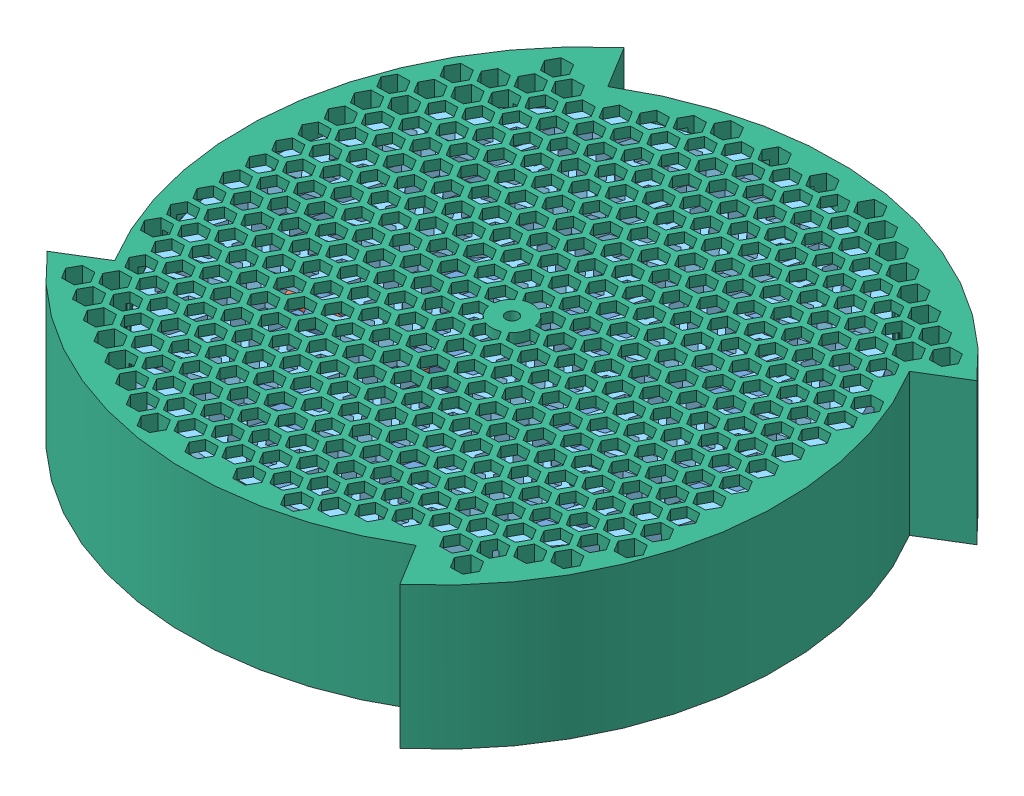
SolidWorks assembly Prototype without internals, configuration Default. Lengths in mm.
Overall size (240.94 41.91 240.94).
9 component instances, 6 part files, 17 mates.
Components (placement in the parent):
- Base-1: Base [Default] at (33.3253 63.9138 106.5179) size (139.7 21.82 139.7)
- Axle-1: Axle [Default] at (56.1853 76.6138 106.5179) x (0 -0.817465 -0.575978) z (1 0 0) size (2.91 3 34.74)
- Axle-2: Axle [Default] at (10.4653 76.6138 106.5179) x (0 -0.966612 0.256244) z (-1 0 0) size (2.91 3 34.74)
- Motor-End Belt-1: Motor-End Belt [Default] at (73.8289 70.2515 121.1027) x (0 -0.000061 1) z (-1 0 0) size (4.5 4.5 3.05)
- Wheel-End Belt-1: Wheel-End Belt [Default] at (73.5749 67.8424 145.4831) x (0 0 1) z (-1 0 0) size (13.65 13.65 3.05)
- Wheel-End Belt-2: Wheel-End Belt [Default] at (-4.5674 67.8424 131.0528) x (0 0 -1) z (1 0 0) size (13.65 13.65 3.05)
- Motor-End Belt-2: Motor-End Belt [Default] at (-4.8214 75.7125 90.6314) x (0 0.347219 -0.937784) z (1 0 0) size (4.5 4.5 3.05)
- Case-1: Case [Default] at (33.3253 66.4538 106.5179) x (0.716089 0 -0.698009) z (0.698009 0 0.716089) size (139.7 31.75 150.25)
- Spinny Boi-1: Spinny Boi [Default] at (33.3253 100.7438 106.5179) x (0.521586 0 0.853199) z (-0.853199 0 0.521586) size (175.26 36.83 175.26)
Mates (geometry in assembly coordinates):
- Coincident12: coincident anti-aligned: plane of Base-1 through (56.1853 76.6138 106.5179) normal (-1 0 0); plane of Axle-1 through (56.1853 76.6138 106.5179) normal (1 0 0)
- Coincident14: coincident: line of Base-1 through (-36.5247 76.6138 106.5179) axis (1 0 0); point of Axle-1
- Coincident17: coincident aligned: plane of Base-1 through (10.4653 76.6138 106.5179) normal (1 0 0); plane of Axle-2 through (10.4653 76.6138 106.5179) normal (1 0 0)
- Coincident18: coincident aligned: line of Base-1 through (-36.5247 76.6138 106.5179) axis (1 0 0); line of Axle-2 through (-24.2747 76.6138 106.5179) axis (1 0 0)
- Coincident24: coincident aligned: plane of Motor-End Belt-1 through (72.3049 76.6138 106.5179) normal (-1 0 0); plane of Wheel-End Belt-1 through (72.3049 67.8424 145.4831) normal (-1 0 0)
- Parallel4: parallel anti-aligned: plane of Base-1 through (33.3253 63.9138 106.5179) normal (1 0 0); plane of Wheel-End Belt-1 through (72.3049 67.8424 145.4831) normal (-1 0 0)
- Coincident27: coincident anti-aligned: line of Axle-1 through (90.9253 76.6138 106.5179) axis (-1 0 0); line of Motor-End Belt-1 through (72.5589 76.6138 106.5179) axis (1 0 0)
- Parallel5: parallel anti-aligned: plane of Axle-1 through (95.1061 75.7512 107.7451) normal (0 -1 -0.000061); plane of Motor-End Belt-1 through (72.5589 75.6129 121.103) normal (0 1 0.000061)
- Distance7: distance = 36.6227 mm aligned: plane of Wheel-End Belt-2 through (-3.2974 67.8424 131.0528) normal (1 0 0); plane of Base-1 through (33.3253 63.9138 106.5179) normal (1 0 0)
- Coincident32: coincident aligned: plane of Wheel-End Belt-2 through (-3.2974 67.8424 131.0528) normal (1 0 0); plane of Motor-End Belt-2 through (-3.2974 76.6138 106.5179) normal (1 0 0)
- Parallel11: parallel anti-aligned: plane of Axle-2 through (-28.4555 76.2311 105.0676) normal (0 -0.937784 -0.347219); plane of Motor-End Belt-2 through (-3.5514 80.7403 92.493) normal (0 0.937784 0.347219)
- Coincident37: coincident anti-aligned: line of Axle-2 through (-24.2747 76.6138 106.5179) axis (1 0 0); line of Motor-End Belt-2 through (-3.5514 76.6138 106.5179) axis (-1 0 0)
- Distance8: distance = 38.9797 mm anti-aligned: plane of Wheel-End Belt-1 through (72.3049 67.8424 145.4831) normal (-1 0 0); plane of Base-1 through (33.3253 63.9138 106.5179) normal (1 0 0)
- Concentric3: concentric aligned: cylinder of Base-1 through (33.3253 66.4538 106.5179) axis (0 -1 0) radius 69.85; cylinder of Case-1 through (33.3253 98.2038 106.5179) axis (0 -1 0) radius 69.85
- Coincident40: coincident anti-aligned: plane of Base-1 through (33.3253 66.4538 106.5179) normal (0 1 0); plane of Case-1 through (33.3253 66.4538 106.5179) normal (0 -1 0)
- Coincident41: coincident anti-aligned: plane of Case-1 through (33.3253 98.2038 106.5179) normal (0 1 0); plane of Spinny Boi-1 through (33.3253 98.2038 106.5179) normal (0 -1 0)
- Concentric4: concentric anti-aligned: cylinder of Case-1 through (33.3253 98.2038 106.5179) axis (0 -1 0) radius 69.85; cylinder of Spinny Boi-1 through (33.3253 63.9138 106.5179) axis (0 1 0) radius 71.12
